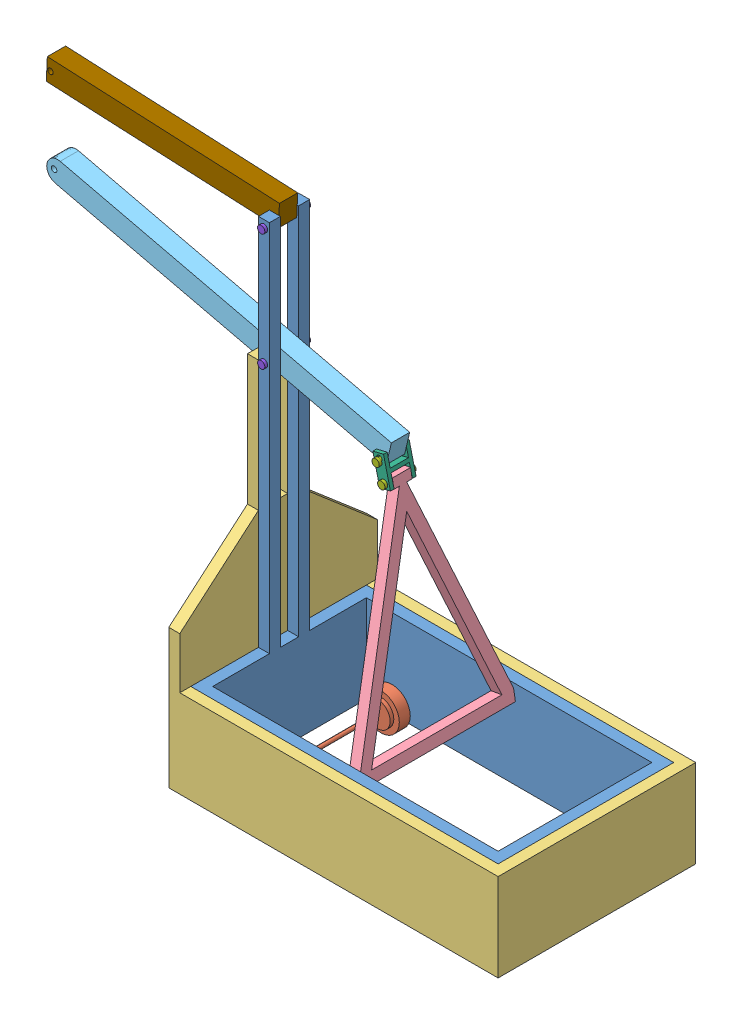
SolidWorks assembly Assem1, configuration Default. Lengths in mm.
Overall size (3771.27 3454.48 1371.6).
12 component instances, 9 part files, 24 mates.
Components (placement in the parent):
- Base-1: Base [Default] at (363.8735 651.2667 3587.1664) size (2133.6 3200.4 1219.2)
- Wheels-1: Wheels [Default] at (643.2735 727.4667 3485.5664) size (254 254 1168.4)
- Wheels-2: Wheels [Default] at (2218.0735 727.4667 3485.5664) x (0.622304 0.782776 0) z (0 0 1) size (254 254 1168.4)
- Mat-1: Mat [Default] at (287.6735 651.2667 3663.3664) size (2286 2336.8 1371.6)
- Triangle.Holder-1: Triangle.Holder [Default] at (1474.6256 1153.4989 2977.5664) x (0 0 1) z (-0.985826 -0.167773 0) size (1168.4 1535.42 76.2)
- Post-1: Post [Default] at (1175.4787 2727.0304 2914.0664) x (0 0 1) z (-0.97321 0.229918 0) size (127 152.4 2438.4)
- Connector.Tri.Post-1: Connector.Tri.Post [Default] at (1107.3718 2787.1103 2888.6664) x (0 0 1) z (0.971854 0.235584 0) size (177.8 203.2 76.2)
- Pin.Tri.Post-2: Pin.Tri.Post [Default] at (1184.7903 2629.4617 2869.6164) size (50.8 50.8 215.9)
- Pin.Tri.Post-3: Pin.Tri.Post [Default] at (1145.4354 2744.5932 2869.6164) size (50.8 50.8 215.9)
- Pin.Post.Base-1: Pin.Post.Base [Default] at (401.9735 3800.8667 2818.8164) size (50.8 50.8 317.5)
- Pin.Post.Base-2: Pin.Post.Base [Default] at (401.9735 2988.0667 2818.8164) size (50.8 50.8 317.5)
- Post.2-1: Post.2 [Default] at (426.132 3774.2831 2914.0664) x (0 0 1) z (-0.047738 -0.99886 0) size (127 1612.9 152.4)
Mates (geometry in assembly coordinates):
- Coincident1: coincident anti-aligned: plane of Base-1 through (440.0735 651.2667 3510.9664) normal (0 0 -1); plane of Wheels-1 through (643.2735 727.4667 3510.9664) normal (0 0 1)
- Concentric2: concentric aligned: cylinder of Base-1 through (643.2735 727.4667 3561.7664) axis (0 0 -1) radius 12.7; cylinder of Wheels-1 through (643.2735 727.4667 3561.7664) axis (0 0 -1) radius 12.7
- Concentric3: concentric aligned: cylinder of Base-1 through (2218.0735 727.4667 3561.7664) axis (0 0 -1) radius 12.7; cylinder of Wheels-2 through (2218.0735 727.4667 3561.7664) axis (0 0 -1) radius 12.7
- Coincident2: coincident anti-aligned: plane of Base-1 through (440.0735 651.2667 3510.9664) normal (0 0 -1); plane of Wheels-2 through (2218.0735 727.4667 3510.9664) normal (0 0 1)
- Coincident3: coincident anti-aligned: plane of Base-1 through (363.8735 1260.8667 3587.1664) normal (-1 0 0); plane of Mat-1 through (363.8735 651.2667 2367.9664) normal (1 0 0)
- Coincident5: coincident anti-aligned: plane of Base-1 through (2497.4735 1260.8667 3587.1664) normal (1 0 0); plane of Mat-1 through (2497.4735 651.2667 2367.9664) normal (-1 0 0)
- Coincident6: coincident anti-aligned: plane of Base-1 through (363.8735 1260.8667 3587.1664) normal (0 0 1); plane of Mat-1 through (363.8735 651.2667 3587.1664) normal (0 0 -1)
- Coincident7: coincident aligned: plane of Base-1 through (363.8735 1260.8667 3587.1664) normal (0 1 0); plane of Mat-1 through (287.6735 1260.8667 3663.3664) normal (0 1 0)
- Concentric4: concentric anti-aligned: cylinder of Base-1 through (1430.6735 1184.6667 2393.3664) axis (0 0 1) radius 12.7; cylinder of Triangle.Holder-1 through (1430.6735 1184.6667 3561.7664) axis (0 0 -1) radius 12.7
- Coincident8: coincident anti-aligned: plane of Base-1 through (440.0735 651.2667 3510.9664) normal (0 0 -1); plane of Triangle.Holder-1 through (1399.5057 1140.7146 3510.9664) normal (0 0 1)
- Coincident11: coincident anti-aligned: plane of Base-1 through (363.8735 3851.6667 3041.0664) normal (0 0 -1); plane of Post-1 through (-1197.5963 3287.6636 3041.0664) normal (0 0 1)
- Concentric7: concentric aligned: cylinder of Base-1 through (401.9735 2988.0667 526.4664) axis (0 0 1) radius 19.05; cylinder of Post-1 through (401.9735 2988.0667 2879.0144) axis (0 0 1) radius 19.05
- Concentric8: concentric anti-aligned: cylinder of Post-1 through (1151.8792 2765.2297 2879.0144) axis (0 0 1) radius 19.05; cylinder of Connector.Tri.Post-1 through (1151.8792 2765.2297 3088.5644) axis (0 0 -1) radius 19.05
- Coincident12: coincident anti-aligned: plane of Post-1 through (-1197.5963 3287.6636 2914.0664) normal (0 0 -1); plane of Connector.Tri.Post-1 through (1107.3718 2787.1103 2914.0664) normal (0 0 1)
- Coincident13: coincident anti-aligned: circle of Triangle.Holder-1; cylinder of Connector.Tri.Post-1 through (1184.7903 2629.4617 3088.5644) axis (0 0 -1) radius 19.05
- Concentric9: concentric aligned: cylinder of Connector.Tri.Post-1 through (1184.7903 2629.4617 3088.5644) axis (0 0 -1) radius 19.05; cylinder of Pin.Tri.Post-2 through (1184.7903 2629.4617 3066.4664) axis (0 0 -1) radius 19.05
- Coincident15: coincident anti-aligned: plane of Connector.Tri.Post-1 through (1181.427 2805.0618 2888.6664) normal (0 0 -1); plane of Pin.Tri.Post-2 through (1184.7903 2629.4617 2888.6664) normal (0 0 1)
- Coincident16: coincident anti-aligned: plane of Connector.Tri.Post-1 through (1181.427 2805.0618 3066.4664) normal (0 0 1); plane of Pin.Tri.Post-3 through (1145.4354 2744.5932 3066.4664) normal (0 0 -1)
- Coincident17: coincident anti-aligned: cylinder of Base-1 through (401.9735 3800.8667 4361.8664) axis (0 0 -1) radius 19.05; circle of Post.2-1
- Coincident18: coincident anti-aligned: plane of Base-1 through (363.8735 3851.6667 3041.0664) normal (0 0 -1); plane of Post.2-1 through (-1184.9291 3851.2797 3041.0664) normal (0 0 1)
- Concentric13: concentric: cylinder of Base-1 through (401.9735 3800.8667 4361.8664) axis (0 0 -1) radius 19.05; cylinder of Pin.Post.Base-1 through (401.9735 3800.8667 3117.2664) axis (0 0 -1) radius 19.05
- Coincident20: coincident anti-aligned: plane of Base-1 through (363.8735 3851.6667 2837.8664) normal (0 0 -1); plane of Pin.Post.Base-1 through (401.9735 3800.8667 2837.8664) normal (0 0 1)
- Coincident21: coincident: circle of Base-1; cylinder of Pin.Post.Base-2 through (401.9735 2988.0667 3117.2664) axis (0 0 -1) radius 19.05
- Coincident22: coincident anti-aligned: plane of Base-1 through (363.8735 3851.6667 3117.2664) normal (0 0 1); plane of Pin.Post.Base-2 through (401.9735 2988.0667 3117.2664) normal (0 0 -1)
